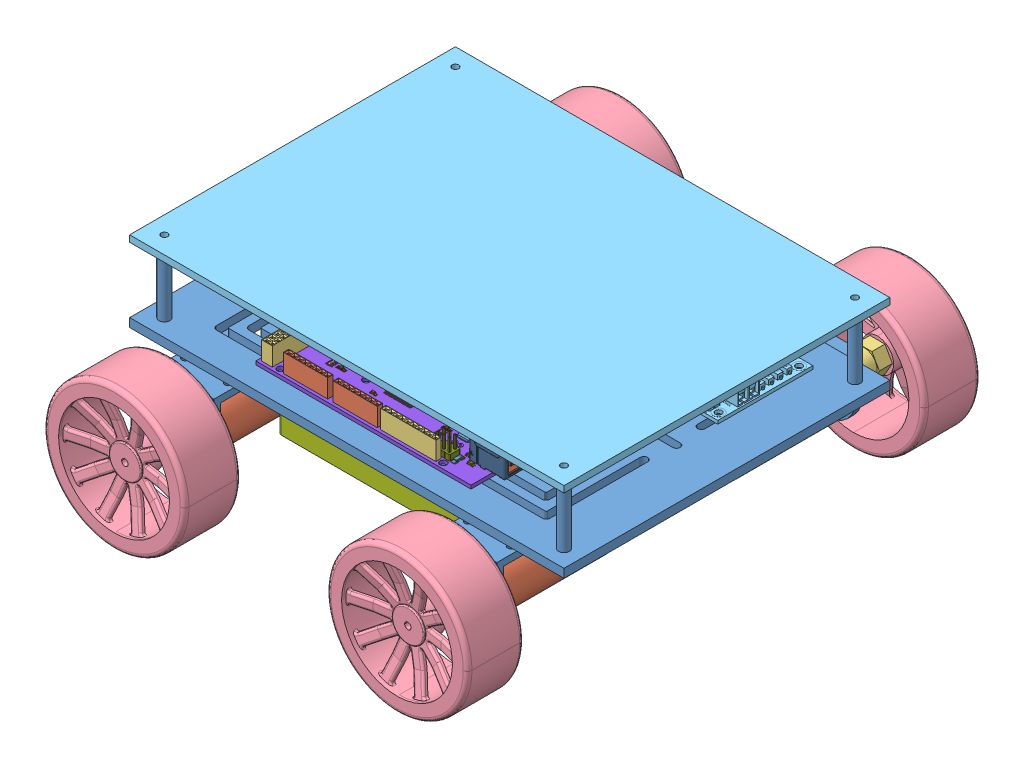
SolidWorks assembly 組合件1, configuration 預設. Lengths in mm.
Overall size (200 87.4 236.21).
90 component instances, 43 part files, 43 mates.
Components (placement in the parent):
- 底板-2: 底板 [預設] at (-50.2198 200.9858 55.6181) size (200 65.05 168.3)
- 馬達-1: 馬達 [Default] at (-115.3698 183.0858 84.7681) size (24.2 24.2 64)
- 馬達-2: 馬達 [Default] at (-115.3698 183.0858 26.4681) x (-1 0 0) z (0 0 -1) size (24.2 24.2 64)
- 馬達-3: 馬達 [Default] at (14.9302 183.0858 84.7681) size (24.2 24.2 64)
- 馬達-4: 馬達 [Default] at (14.9302 183.0858 24.2601) x (-1 0 0) z (0 0 -1) size (24.2 24.2 64)
- 聯軸器-1: 聯軸器 [Default] at (14.9302 183.0858 -48.5899) size (13.86 12 18.85)
- 聯軸器-2: 聯軸器 [Default] at (-115.3698 183.0858 157.6181) x (1 0 0) z (0 0 -1) size (13.86 12 18.85)
- 聯軸器-3: 聯軸器 [Default] at (-115.3698 183.0858 -46.3819) size (13.86 12 18.85)
- 聯軸器-4: 聯軸器 [Default] at (14.9302 183.0858 157.6181) x (-1 0 0) z (0 0 -1) size (13.86 12 18.85)
- prt0003.stp-2: prt0003.stp [Default] at (-115.3698 183.0858 -35.3819) x (0 0 -1) z (1 0 0) size (26 65 65)
- prt0003.stp-3: prt0003.stp [Default] at (14.9302 183.0858 -37.5899) x (0 0 -1) z (1 0 0) size (26 65 65)
- prt0003.stp-4: prt0003.stp [Default] at (14.9302 183.0858 146.6181) x (0 0 1) z (-1 0 0) size (26 65 65)
- prt0003.stp-5: prt0003.stp [Default] at (-115.3698 183.0858 146.6181) x (0 0 1) z (-1 0 0) size (26 65 65)
- l298n-4: l298n [Predeterminado] at (-15.2198 204.9858 37.7431) size (43 29.51 43.75)
- l298n-5: l298n [Predeterminado] at (-128.2198 204.9858 37.7431) size (43 29.51 43.75)
- 麵包版-1: 麵包版 [Default] at (-51.1378 204.9858 63.1681) x (0 0 -1) z (1 0 0) size (82.55 9.02 55.12)
- 電池盒1-1: 電池盒1 [Default] at (-3.0053 177.9858 38.6181) x (0 0 -1) z (0 1 0) size (43 95 23)
- 電池盒1-2: 電池盒1 [Default] at (-5.1496 177.9858 115.6181) x (0 0 -1) z (0 1 0) size (43 95 23)
- User Library-arduino_MEGA2650-1-1: User Library-arduino_MEGA2650-1 [Default] at (-3.152 206.5858 67.1181) x (0 0 -1) z (1 0 0) size (53.34 15.25 107.95)
  - User Library-arduino_MEGA2650-1_MEGAboard-1: User Library-arduino_MEGA2650-1_MEGAboard [Default] at origin size (53.34 1.6 101.6)
  - User Library-arduino_MEGA2650-1_47uf CAP Dcase-1: User Library-arduino_MEGA2650-1_47uf CAP Dcase [Default] at (-9.144 0 -18.415) x (0 0 -1) z (1 0 0) size (6.6 5.81 8)
  - User Library-arduino_MEGA2650-1_USB SHELL-1: User Library-arduino_MEGA2650-1_USB SHELL [Default] at (-38.02 0.43 6.35) size (13.72 15.2 16.51)
  - User Library-arduino_MEGA2650-1_USB core-1: User Library-arduino_MEGA2650-1_USB core [Default] at (-38.02 0.43 6.35) size (11.3 10.68 15.75)
  - User Library-arduino_MEGA2650-1_usb top contact-1: User Library-arduino_MEGA2650-1_usb top contact [Default] at (-36.77 6.52 5.97) size (1 9.67 13.76)
  - User Library-arduino_MEGA2650-1_usb btm contact-1: User Library-arduino_MEGA2650-1_usb btm contact [Default] at (-36.77 4.84 5.97) size (1 6.84 11.76)
  - User Library-arduino_MEGA2650-1_usb btm contact-2: User Library-arduino_MEGA2650-1_usb btm contact [Default] at (-39.27 4.84 5.97) size (1 6.84 11.76)
  - User Library-arduino_MEGA2650-1_usb top contact-2: User Library-arduino_MEGA2650-1_usb top contact [Default] at (-39.27 6.52 5.97) size (1 9.67 13.76)
  - User Library-arduino_MEGA2650-1_power jack-1: User Library-arduino_MEGA2650-1_power jack [Default] at (-7.675 0 1.905) size (11.2 15.2 15.9)
  - User Library-arduino_MEGA2650-1_47uf CAP Dcase-2: User Library-arduino_MEGA2650-1_47uf CAP Dcase [Default] at (-9.144 0 -25.527) x (0 0 -1) z (1 0 0) size (6.6 5.81 8)
  - User Library-arduino_MEGA2650-1_crystal-1: User Library-arduino_MEGA2650-1_crystal [Default] at (-26.035 0 -18.415) x (1 0 0) z (0 0 -1) size (4 5 11)
  - User Library-arduino_MEGA2650-1_2pin_header__02-1: User Library-arduino_MEGA2650-1_2pin_header__02 [Default] at (-46.23 0 -15.75) size (5 11.75 2.54)
  - User Library-arduino_MEGA2650-1_reg-1: User Library-arduino_MEGA2650-1_reg [Default] at (-17.78 0 -8.636) size (6.5 1.69 8.3)
  - User Library-arduino_MEGA2650-1_led-1: User Library-arduino_MEGA2650-1_led [Default] at (-34.29 0 -27.94) x (0 0 1) z (-1 0 0) size (4 0.9 1.55)
  - User Library-arduino_MEGA2650-1_2pin_header__02-2: User Library-arduino_MEGA2650-1_2pin_header__02 [Default] at (-30.43 0 -64.91) x (0 0 1) z (-1 0 0) size (5 11.75 2.54)
  - User Library-arduino_MEGA2650-1_2pin_header__02-3: User Library-arduino_MEGA2650-1_2pin_header__02 [Default] at (-27.89 0 -64.91) x (0 0 1) z (-1 0 0) size (5 11.75 2.54)
  - User Library-arduino_MEGA2650-1_2pin_header__02-4: User Library-arduino_MEGA2650-1_2pin_header__02 [Default] at (-25.35 0 -64.91) x (0 0 1) z (-1 0 0) size (5 11.75 2.54)
  - User Library-arduino_MEGA2650-1_2pin_header__02-5: User Library-arduino_MEGA2650-1_2pin_header__02 [Default] at (-46.23 0 -18.29) size (5 11.75 2.54)
  - User Library-arduino_MEGA2650-1_2pin_header__02-6: User Library-arduino_MEGA2650-1_2pin_header__02 [Default] at (-46.23 0 -20.83) size (5 11.75 2.54)
  - User Library-arduino_MEGA2650-1_atmega16u2-1: User Library-arduino_MEGA2650-1_atmega16u2 [Default] at (-34.671 0.06 -20) x (1 0 0) z (0 0 -1) size (5.5 1.01 5.5)
  - User Library-arduino_MEGA2650-1_led-2: User Library-arduino_MEGA2650-1_led [Default] at (-36.576 0 -27.94) x (0 0 -1) z (1 0 0) size (4 0.9 1.55)
  - User Library-arduino_MEGA2650-1_led-3: User Library-arduino_MEGA2650-1_led [Default] at (-42.164 0 -27.94) x (0 0 1) z (-1 0 0) size (4 0.9 1.55)
  - User Library-arduino_MEGA2650-1_led-4: User Library-arduino_MEGA2650-1_led [Default] at (-36.83 0 -76.2) x (0 0 1) z (-1 0 0) size (4 0.9 1.55)
  - User Library-arduino_MEGA2650-1_8 PORT HEADER-1: User Library-arduino_MEGA2650-1_8 PORT HEADER [Default] at (-50.8 0 -45.72) x (0 0 -1) z (1 0 0) size (20.32 10.51 2.41)
  - User Library-arduino_MEGA2650-1_8 PORT HEADER-2: User Library-arduino_MEGA2650-1_8 PORT HEADER [Default] at (-2.54 0 -27.94) x (0 0 -1) z (1 0 0) size (20.32 10.51 2.41)
  - User Library-arduino_MEGA2650-1_8 PORT HEADER-3: User Library-arduino_MEGA2650-1_8 PORT HEADER [Default] at (-2.54 0 -50.8) x (0 0 -1) z (1 0 0) size (20.32 10.51 2.41)
  - User Library-arduino_MEGA2650-1_10 PORT HEADER-1: User Library-arduino_MEGA2650-1_10 PORT HEADER [Default] at (-50.8 0 -18.796) x (0 0 -1) z (1 0 0) size (25.4 10.51 2.41)
  - User Library-arduino_MEGA2650-1_102 RESISTOR PACK-1: User Library-arduino_MEGA2650-1_102 RESISTOR PACK [Default] at (-36.83 0 -80.645) size (3.2 0.51 3)
  - User Library-arduino_MEGA2650-1_102 RESISTOR PACK-2: User Library-arduino_MEGA2650-1_102 RESISTOR PACK [Default] at (-39.37 0 -27.94) size (3.2 0.51 3)
  - User Library-arduino_MEGA2650-1_103 RESISTOR PACK-1: User Library-arduino_MEGA2650-1_103 RESISTOR PACK [Default] at (-31.115 0 -27.94) size (3.2 0.51 3)
  - User Library-arduino_MEGA2650-1_220 RESISTOR PACK-1: User Library-arduino_MEGA2650-1_220 RESISTOR PACK [Default] at (-37.084 0 -12.065) size (3.2 0.51 3)
  - User Library-arduino_MEGA2650-1_16mhz crystal - measured-1: User Library-arduino_MEGA2650-1_16mhz crystal - measured [Default] at (-14.605 0 -38.354) size (3.4 0.8 2)
  - User Library-arduino_MEGA2650-1_PADS001-1: User Library-arduino_MEGA2650-1_PADS001 [Default] at (-39.878 0.1 -18.288) x (-1 0 0) z (0 0 1) size (4.54 0.1 4.54)
  - User Library-arduino_MEGA2650-1_603 cap on pad-1: User Library-arduino_MEGA2650-1_603 cap on pad [Default] at (-44.45 0 -27.94) x (0 0 -1) z (1 0 0) size (2.76 0.91 1.02)
  - User Library-arduino_MEGA2650-1_ssot3-1: User Library-arduino_MEGA2650-1_ssot3 [Default] at (-25.908 0 -9.144) x (-1 0 0) z (0 0 -1) size (3 1.13 3.09)
  - User Library-arduino_MEGA2650-1_mf-msmf050-2-1: User Library-arduino_MEGA2650-1_mf-msmf050-2 [Default] at (-26.67 0 -4.445) size (5.76 1.02 3.72)
  - User Library-arduino_MEGA2650-1_603 cap on pad-2: User Library-arduino_MEGA2650-1_603 cap on pad [Default] at (-29.337 0 -24.765) x (0 0 1) z (-1 0 0) size (2.76 0.91 1.02)
  - User Library-arduino_MEGA2650-1_603 cap on pad-3: User Library-arduino_MEGA2650-1_603 cap on pad [Default] at (-30.988 0 -12.065) x (0 0 -1) z (1 0 0) size (2.76 0.91 1.02)
  - User Library-arduino_MEGA2650-1_lmv358-1: User Library-arduino_MEGA2650-1_lmv358 [Default] at (-25.146 0 -27.94) size (3.7 1.4 2.9)
  - User Library-arduino_MEGA2650-1_603 cap on pad-4: User Library-arduino_MEGA2650-1_603 cap on pad [Default] at (-17.653 0 -14.351) size (2.76 0.91 1.02)
  - User Library-arduino_MEGA2650-1_603 cap on pad-5: User Library-arduino_MEGA2650-1_603 cap on pad [Default] at (-29.337 0 -12.065) x (0 0 1) z (-1 0 0) size (2.76 0.91 1.02)
  - User Library-arduino_MEGA2650-1_603 cap on pad-6: User Library-arduino_MEGA2650-1_603 cap on pad [Default] at (-29.337 0 -21.59) x (0 0 1) z (-1 0 0) size (2.76 0.91 1.02)
  - User Library-arduino_MEGA2650-1_603 cap on pad-7: User Library-arduino_MEGA2650-1_603 cap on pad [Default] at (-29.337 0 -15.24) x (0 0 1) z (-1 0 0) size (2.76 0.91 1.02)
  - User Library-arduino_MEGA2650-1_603 cap on pad-8: User Library-arduino_MEGA2650-1_603 cap on pad [Default] at (-42.291 0 -12.065) x (0 0 1) z (-1 0 0) size (2.76 0.91 1.02)
  - User Library-arduino_MEGA2650-1_lp2985dgkr-1: User Library-arduino_MEGA2650-1_lp2985dgkr [Default] at (-21.336 0 -18.415) x (0 0 -1) z (1 0 0) size (5.85 1.1 3)
  - User Library-arduino_MEGA2650-1_cd1206 diode-1: User Library-arduino_MEGA2650-1_cd1206 diode [Default] at (-14.605 0 -35.56) x (0 0 1) z (-1 0 0) size (2.09 0.96 5)
  - User Library-arduino_MEGA2650-1_cd1206 diode-2: User Library-arduino_MEGA2650-1_cd1206 diode [Default] at (-46.228 0 -13.081) x (0 0 1) z (-1 0 0) size (2.09 0.96 5)
  - User Library-arduino_MEGA2650-1_603 resistor-1: User Library-arduino_MEGA2650-1_603 resistor [Default] at (-29.337 0 -18.415) x (0 0 1) z (-1 0 0) size (2.36 0.62 1.03)
  - User Library-arduino_MEGA2650-1_blm21-1: User Library-arduino_MEGA2650-1_blm21 [Default] at (-45.085 0 -8.255) x (0 0 -1) z (1 0 0) size (2.78 0.95 1.32)
  - User Library-arduino_MEGA2650-1_m7 diode-1: User Library-arduino_MEGA2650-1_m7 diode [Default] at (-2.794 0 -21.59) x (0 0 -1) z (1 0 0) size (6.66 2.35 2.5)
  - User Library-arduino_MEGA2650-1_MLC0603-1: User Library-arduino_MEGA2650-1_MLC0603 [Default] at (-34.29 0 -12.065) x (0 0 -1) z (1 0 0) size (2.36 0.6 1.03)
  - User Library-arduino_MEGA2650-1_MLC0603-2: User Library-arduino_MEGA2650-1_MLC0603 [Default] at (-39.878 0 -12.065) x (0 0 -1) z (1 0 0) size (2.36 0.6 1.03)
  - User Library-arduino_MEGA2650-1_RESET CORE-1: User Library-arduino_MEGA2650-1_RESET CORE [Default] at (-27.94 0.1 -74.168) x (0 0 1) z (-1 0 0) size (6.2 3.1 9.6)
  - User Library-arduino_MEGA2650-1_RESET-1: User Library-arduino_MEGA2650-1_RESET [Default] at (-27.94 0.1 -74.168) size (7.3 2 6.2)
  - User Library-arduino_MEGA2650-1_8 PORT HEADER-4: User Library-arduino_MEGA2650-1_8 PORT HEADER [Default] at (-2.54 0 -73.66) x (0 0 -1) z (1 0 0) size (20.32 10.51 2.41)
  - User Library-arduino_MEGA2650-1_8 PORT HEADER-5: User Library-arduino_MEGA2650-1_8 PORT HEADER [Default] at (-50.8 0 -68.58) x (0 0 -1) z (1 0 0) size (20.32 10.51 2.41)
  - User Library-arduino_MEGA2650-1_603 cap on pad-9: User Library-arduino_MEGA2650-1_603 cap on pad [Default] at (-21.59 0 -27.94) x (0 0 1) z (-1 0 0) size (2.76 0.91 1.02)
  - User Library-arduino_MEGA2650-1_603 cap on pad-10: User Library-arduino_MEGA2650-1_603 cap on pad [Default] at (-18.288 0 -27.94) x (0 0 1) z (-1 0 0) size (2.76 0.91 1.02)
  - User Library-arduino_MEGA2650-1_103 RESISTOR PACK-2: User Library-arduino_MEGA2650-1_103 RESISTOR PACK [Default] at (-16.51 0 -18.415) size (3.2 0.51 3)
  - User Library-arduino_MEGA2650-1_603 cap on pad-11: User Library-arduino_MEGA2650-1_603 cap on pad [Default] at (-17.145 0 -21.59) x (0 0 -1) z (1 0 0) size (2.76 0.91 1.02)
  - User Library-arduino_MEGA2650-1_603 cap on pad-12: User Library-arduino_MEGA2650-1_603 cap on pad [Default] at (-39.37 0 -58.928) x (0 0 1) z (-1 0 0) size (2.76 0.91 1.02)
  - User Library-arduino_MEGA2650-1_603 cap on pad-13: User Library-arduino_MEGA2650-1_603 cap on pad [Default] at (-14.605 0 -33.528) size (2.76 0.91 1.02)
  - User Library-arduino_MEGA2650-1_603 resistor-2: User Library-arduino_MEGA2650-1_603 resistor [Default] at (-14.605 0 -40.513) x (-1 0 0) z (0 0 -1) size (2.36 0.62 1.03)
  - User Library-arduino_MEGA2650-1_603 cap on pad-14: User Library-arduino_MEGA2650-1_603 cap on pad [Default] at (-7.112 0 -38.608) x (0 0 1) z (-1 0 0) size (2.76 0.91 1.02)
  - User Library-arduino_MEGA2650-1_603 cap on pad-15: User Library-arduino_MEGA2650-1_603 cap on pad [Default] at (-30.4038 0 -40.0558) x (0 0 1) z (-1 0 0) size (2.76 0.91 1.02)
  - User Library-arduino_MEGA2650-1_18 X 2 ROW HEADER-1: User Library-arduino_MEGA2650-1_18 X 2 ROW HEADER [Default] at (-50.8 0 -95.25) size (45.72 10.51 4.95)
  - User Library-arduino_MEGA2650-1_atmega2650-16AU-1: User Library-arduino_MEGA2650-1_atmega2650-16AU [Default] at (-28.3464 0.1 -50.8) x (0 0 1) z (-1 0 0) size (16.8 1.11 16.8)
- 上板-1: 上板 [預設] at (-46.0792 234.9858 64.1409) size (200 3 150)
- 尋跡1-1: 尋跡1 [預設] at (-81.2088 170.9858 40.1181) x (0 0 1) z (1 0 0) size (31 12 46)
- 尋跡銅柱-4: 尋跡銅柱 [預設] at (-110.2198 170.9858 68.8681) size (5 30 5)
- 尋跡銅柱-5: 尋跡銅柱 [預設] at (-110.2198 170.9858 42.3681) size (5 30 5)
Mates (geometry in assembly coordinates):
- 同軸心1: concentric aligned: circle of 底板-2; circle of 馬達-1
- 重合/共線/共點1: coincident anti-aligned: plane of 底板-2 through (-115.3698 183.0858 136.7681) normal (0 0 -1); plane of 馬達-1 through (-115.3698 183.0858 136.7681) normal (0 0 1)
- 同軸心2: concentric aligned: circle of 底板-2; circle of 馬達-2
- 重合/共線/共點2: coincident anti-aligned: plane of 底板-2 through (-115.3698 183.0858 -25.5319) normal (0 0 1); plane of 馬達-2 through (-115.3698 183.0858 -25.5319) normal (0 0 -1)
- 同軸心3: concentric aligned: circle of 底板-2; circle of 馬達-3
- 重合/共線/共點3: coincident anti-aligned: plane of 底板-2 through (14.9302 183.0858 136.7681) normal (0 0 -1); plane of 馬達-3 through (14.9302 183.0858 136.7681) normal (0 0 1)
- 同軸心4: concentric aligned: circle of 底板-2; circle of 馬達-4
- 重合/共線/共點6: coincident anti-aligned: circle of 馬達-4; circle of 聯軸器-1
- 重合/共線/共點8: coincident anti-aligned: circle of 馬達-2; circle of 聯軸器-3
- 重合/共線/共點9: coincident anti-aligned: circle of 馬達-1; circle of 聯軸器-2
- 重合/共線/共點10: coincident anti-aligned: circle of 馬達-3; circle of 聯軸器-4
- 重合/共線/共點11: coincident anti-aligned: plane of 聯軸器-3 through (-115.3698 183.0858 -46.3819) normal (0 0 -1); plane of prt0003.stp-2 through (-115.3698 183.0858 -46.3819) normal (0 0 1)
- 同軸心5: concentric anti-aligned: circle of 聯軸器-3; circle of prt0003.stp-2
- 重合/共線/共點13: coincident anti-aligned: plane of 聯軸器-1 through (14.9302 183.0858 -48.5899) normal (0 0 -1); plane of prt0003.stp-3 through (14.9302 183.0858 -48.5899) normal (0 0 1)
- 同軸心7: concentric anti-aligned: circle of 聯軸器-1; circle of prt0003.stp-3
- 重合/共線/共點14: coincident anti-aligned: plane of 聯軸器-4 through (14.9302 183.0858 157.6181) normal (0 0 1); plane of prt0003.stp-4 through (14.9302 183.0858 157.6181) normal (0 0 -1)
- 同軸心8: concentric anti-aligned: circle of 聯軸器-4; circle of prt0003.stp-4
- 重合/共線/共點15: coincident anti-aligned: plane of 聯軸器-2 through (-115.3698 183.0858 157.6181) normal (0 0 1); plane of prt0003.stp-5 through (-115.3698 183.0858 157.6181) normal (0 0 -1)
- 同軸心9: concentric anti-aligned: circle of 聯軸器-2; circle of prt0003.stp-5
- 重合/共線/共點22: coincident anti-aligned: plane of 底板-2 through (-50.2198 204.9858 55.6181) normal (0 1 0); plane of l298n-4 through (6.2802 204.9858 15.8681) normal (0 -1 0)
- 同軸心10: concentric aligned: circle of 底板-2; circle of l298n-4
- 重合/共線/共點25: coincident anti-aligned: plane of 底板-2 through (-50.2198 204.9858 55.6181) normal (0 1 0); plane of l298n-5 through (-106.7198 204.9858 15.8681) normal (0 -1 0)
- 同軸心11: concentric aligned: circle of 底板-2; circle of l298n-5
- 重合/共線/共點26: coincident anti-aligned: line of 底板-2 through (-150.1688 204.9858 -19.3819) axis (1 0 0); line of 麵包版-1 through (-23.5788 204.9858 -19.3819) axis (-1 0 0)
- 重合/共線/共點27: coincident anti-aligned: plane of 底板-2 through (-50.2198 204.9858 55.6181) normal (0 1 0); plane of 麵包版-1 through (-51.1378 204.9858 63.1681) normal (0 -1 0)
- 平行3: parallel anti-aligned: line of 底板-2 through (-125.2198 204.9858 -4.3819) axis (1 0 0); line of l298n-5 through (-85.2198 204.9858 -6.0069) axis (-1 0 0)
- 平行4: parallel aligned: line of 底板-2 through (-125.2198 204.9858 -4.3819) axis (1 0 0); line of l298n-4 through (-15.2198 206.4958 -6.0069) axis (1 0 0)
- 重合/共線/共點38: coincident anti-aligned: plane of 底板-2 through (-50.2198 200.9858 55.6181) normal (0 -1 0); plane of 電池盒1-2 through (-7.1496 200.9858 74.6181) normal (0 1 0)
- 重合/共線/共點39: coincident aligned: line of 底板-2 through (-102.2198 200.9858 115.6181) axis (1 0 0); line of 電池盒1-2 through (-95.1496 200.9858 115.6181) axis (1 0 0)
- 重合/共線/共點40: coincident anti-aligned: plane of 底板-2 through (-50.2198 200.9858 55.6181) normal (0 -1 0); plane of 電池盒1-1 through (-5.0053 200.9858 -2.3819) normal (0 1 0)
- 重合/共線/共點41: coincident anti-aligned: line of 底板-2 through (-102.2198 200.9858 -4.3819) axis (1 0 0); line of 電池盒1-1 through (-5.0053 200.9858 -4.3819) axis (-1 0 0)
- 重合/共線/共點42: coincident anti-aligned: plane of 底板-2 through (-50.2198 204.9858 55.6181) normal (0 1 0); plane of User Library-arduino_MEGA2650-1-1/User Library-arduino_MEGA2650-1_MEGAboard-1 through (-3.152 204.9858 120.4581) normal (0 -1 0)
- 重合/共線/共點43: coincident aligned: line of 底板-2 through (-102.6654 204.9858 67.1181) axis (1 0 0); line of User Library-arduino_MEGA2650-1-1/User Library-arduino_MEGA2650-1_MEGAboard-1 through (-102.212 204.9858 67.1181) axis (1 0 0)
- 重合/共線/共點44: coincident anti-aligned: circle of 底板-2; plane of 上板-1 through (-46.0792 234.9858 64.1409) normal (0 -1 0)
- 同軸心12: concentric aligned: circle of 底板-2; circle of 上板-1
- 同軸心13: concentric aligned: circle of 底板-2; circle of 上板-1
- 同軸心23: concentric anti-aligned: circle of 底板-2; circle of 尋跡銅柱-4
- 重合/共線/共點52: coincident anti-aligned: plane of 底板-2 through (-50.2198 200.9858 55.6181) normal (0 -1 0); plane of 尋跡銅柱-4 through (-110.2198 200.9858 68.8681) normal (0 1 0)
- 同軸心25: concentric aligned: circle of 底板-2; circle of 尋跡銅柱-5
- 重合/共線/共點54: coincident anti-aligned: plane of 底板-2 through (-50.2198 200.9858 55.6181) normal (0 -1 0); plane of 尋跡銅柱-5 through (-110.2198 200.9858 42.3681) normal (0 1 0)
- 同軸心26: concentric anti-aligned: circle of 尋跡1-1; circle of 尋跡銅柱-4
- 重合/共線/共點55: coincident anti-aligned: plane of 尋跡1-1 through (-81.2088 170.9858 40.1181) normal (0 1 0); plane of 尋跡銅柱-4 through (-110.2198 170.9858 68.8681) normal (0 -1 0)
- 同軸心27: concentric anti-aligned: circle of 尋跡1-1; circle of 尋跡銅柱-5
